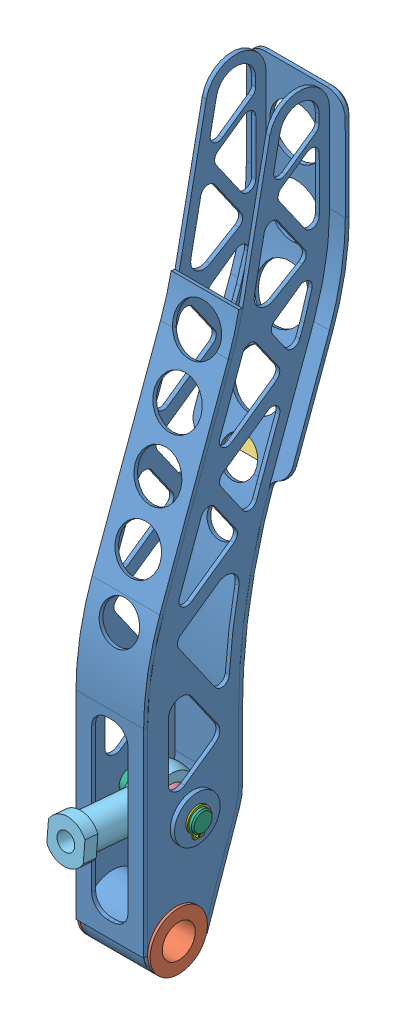
SolidWorks assembly PedalClutch, configuration Default. Lengths in mm.
Overall size (49.29 339.39 110.6).
9 component instances, 7 part files, 13 mates.
Components (placement in the parent):
- PedalClutch-1: PedalClutch [Finished Design] at origin size (49.29 339.39 95.55)
- PedalBushing-1: PedalBushing [Default] at (14 79.0909 -303.7744) x (0 0.443386 0.896331) z (-1 0 0) size (22 22 14)
- PedalBushing-2: PedalBushing [Default] at (-14 79.0909 -303.7744) x (0 0.424048 -0.90564) z (1 0 0) size (22 22 14)
- PedalPadBrake-1: PedalPadBrake [Default] at (0 0.1028 -0.5937) x (0 0.001457 -0.999999) z (1 0 0) size (23.29 116.75 36)
- RodEnd312Fem-1: RodEnd312Fem [Default] at (0 116.8709 -310.2475) x (0 0.996427 -0.084462) z (-1 0 0) size (22 47 23.1) (flexible)
  - RodEndBall312-1: RodEndBall312 [Default] x (0.032333 -0.999477 0) z (0 0 1) size (15.06 15.06 22.2)
  - RodEndRace312Fem-1: RodEndRace312Fem [Default] at origin size (22 47 14)
- PedalClutchPin-1: PedalClutchPin [Default] at (-14.65 116.8709 -310.2475) size (34.54 11.94 11.94)
- Basic External Retaining Ring_AI-1: Basic External Retaining Ring_AI [B27.1 - NA1-31] at (15.3866 116.8709 -310.2475) x (0 0 -1) z (1 0 0) size (9 10.67 0.64)
Mates (geometry in assembly coordinates):
- Concentric10: concentric: cylinder of assembly; cylinder of assembly; cylinder of PedalClutch-1 through (42.5127 79.0909 -303.7744) axis (-1 0 0) radius 8; cylinder of PedalBushing-1 through (14 79.0909 -303.7744) axis (1 0 0) radius 8
- Coincident10: coincident: plane of assembly; plane of assembly; plane of PedalClutch-1 through (13 326.2909 -351.1509) normal (1 0 0); plane of PedalBushing-1 through (13 88.9506 -308.6516) normal (-1 0 0)
- Concentric11: concentric: cylinder of assembly; cylinder of assembly; cylinder of PedalBushing-2 through (-14 79.0909 -303.7744) axis (-1 0 0) radius 8; cylinder of PedalClutch-1 through (42.5127 79.0909 -303.7744) axis (-1 0 0) radius 8
- Coincident11: coincident: plane of assembly; plane of assembly; plane of PedalClutch-1 through (-13 326.2909 -351.1509) normal (-1 0 0); plane of PedalBushing-2 through (-13 89.053 -299.1099) normal (1 0 0)
- Coincident18: coincident: plane of PedalPadBrake-1 through (0 0.1028 -0.5937) normal (1 0 0); plane of assembly through (0 0 0) normal (1 0 0)
- Concentric12: concentric: cylinder of assembly; cylinder of assembly; cylinder of PedalClutch-1 through (0 270.6354 -254.9739) axis (0 -0.343726 -0.93907) radius 10; cylinder of PedalPadBrake-1 through (0 249.6714 -312.2483) axis (0 -0.343726 -0.93907) radius 11
- Coincident21: coincident: plane of assembly; plane of assembly; plane of PedalClutch-1 through (-19 212.2207 -341.369) normal (0 -0.343726 -0.93907); plane of PedalPadBrake-1 through (-18 215.5081 -342.5723) normal (0 0.343726 0.93907)
- Concentric13: concentric: cylinder of assembly; cylinder of assembly; cylinder of PedalClutch-1 through (-19 116.8709 -310.2475) axis (1 0 0) radius 4; cylinder of RodEnd312Fem-1/RodEndBall312-1 through (-31.259 116.8709 -310.2475) axis (-1 0 0) radius 3.9688
- Coincident22: coincident: plane of assembly through (0 0 0) normal (1 0 0); plane of RodEnd312Fem-1/RodEndBall312-1 through (0 116.8709 -310.2475) normal (-1 0 0); plane of assembly
- Concentric19: concentric: cylinder of assembly; cylinder of assembly; cylinder of RodEnd312Fem-1/RodEndBall312-1 through (-31.259 116.8709 -310.2475) axis (-1 0 0) radius 3.9688; cylinder of PedalClutchPin-1 through (-34.8491 116.8709 -310.2475) axis (-1 0 0) radius 3.9688
- Coincident28: coincident: plane of assembly; plane of assembly; plane of PedalClutch-1 through (-14.65 116.8709 -310.2475) normal (-1 0 0); plane of PedalClutchPin-1 through (-14.65 120.8397 -310.2475) normal (1 0 0)
- Concentric20: concentric: cylinder of assembly; cylinder of assembly; cylinder of PedalClutchPin-1 through (-34.8491 116.8709 -310.2475) axis (-1 0 0) radius 3.9688; cylinder of Basic External Retaining Ring_AI-1 through (14.7516 116.8709 -310.2475) axis (1 0 0) radius 3.683
- Coincident29: coincident: plane of assembly; plane of assembly; plane of PedalClutchPin-1 through (15.3866 120.5539 -310.2475) normal (-1 0 0); plane of Basic External Retaining Ring_AI-1 through (15.3866 116.8709 -310.2475) normal (1 0 0)
